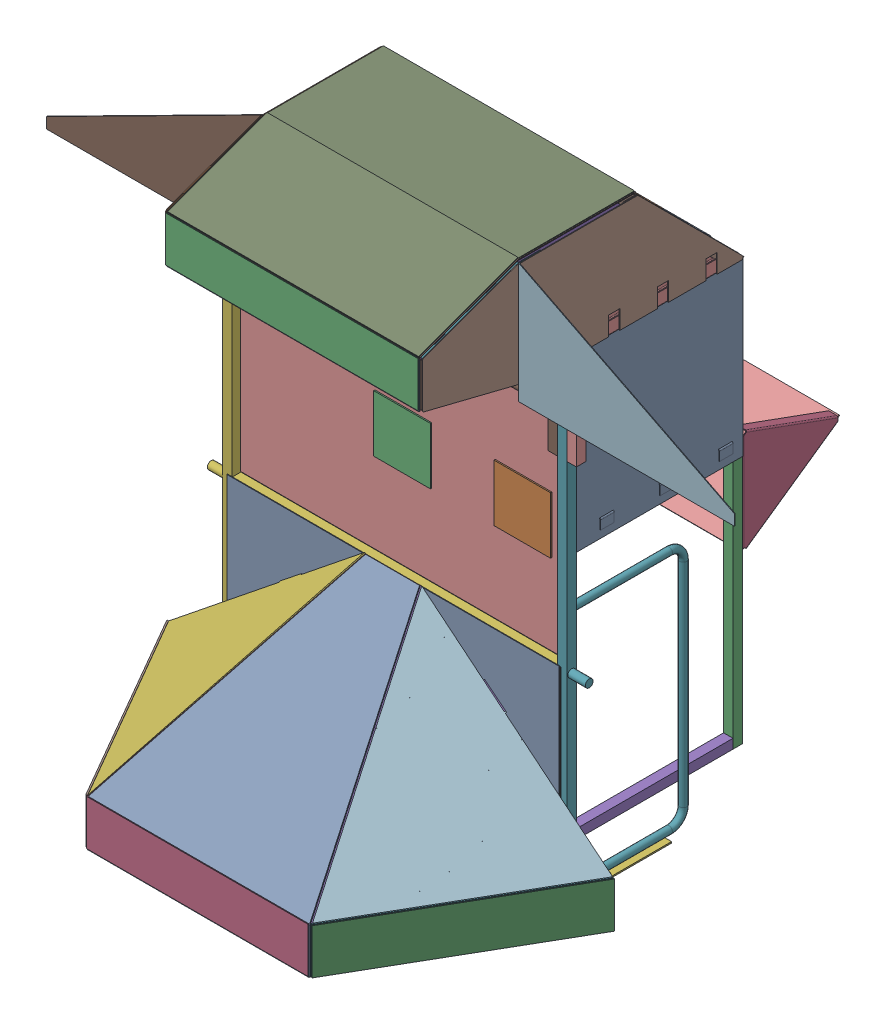
SolidWorks assembly SpeakerDF, configuration Default. Lengths in mm.
Overall size (3235.32 2507.36 2438.57).
2 component instances, 2 part files, 2 mates.
Components (placement in the parent):
- Speaker_defeature-1: Speaker_defeature [Default] at origin size (3235.32 2504.38 2437.49)
- SpeaklerCol-1: SpeaklerCol [Default] at (3.1433 -13.741 7.6578) size (2099.3 2504.38 1961.35)
Mates (geometry in assembly coordinates):
- Coincident1: coincident: line of Speaker_defeature-1 through (381.6615 1497.1937 1702.0177) axis (1 0 0); line of SpeaklerCol-1 through (193.9477 1497.1937 1702.0177) axis (1 0 0)
- Coincident4: coincident aligned: plane of Speaker_defeature-1 through (1671.2351 -625.8635 1834.7072) normal (0.586237 0.73605 0.338464); plane of SpeaklerCol-1 through (1666.8622 -622.8799 1835.7931) normal (0.586237 0.73605 0.338464)
